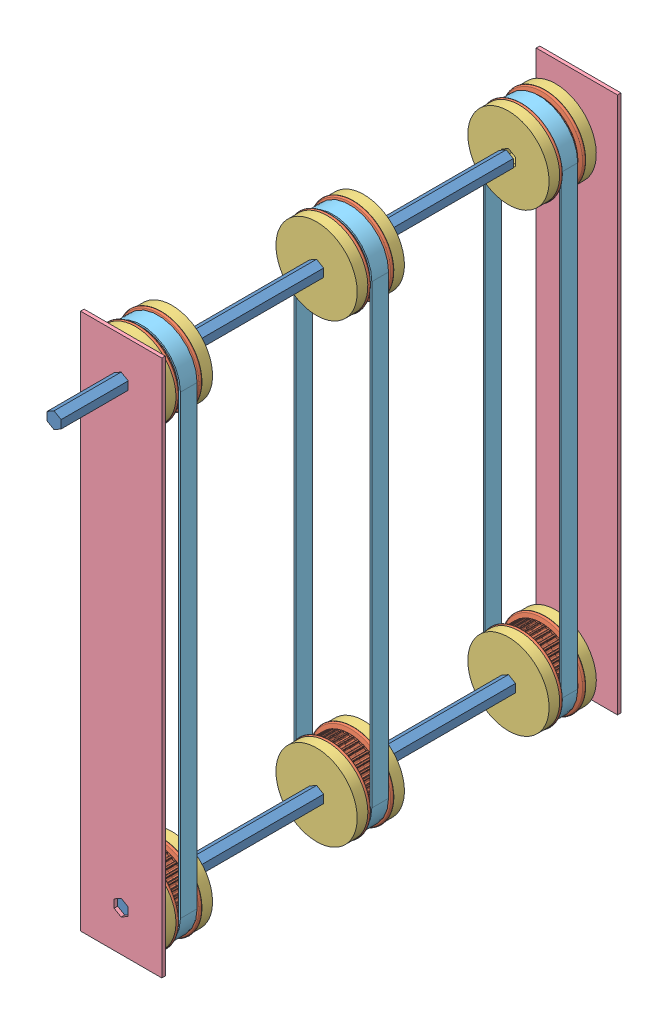
SolidWorks assembly Collection, configuration Default. Lengths in mm.
Overall size (103.22 501.51 473.08).
38 component instances, 5 part files, 17 mates.
Components (placement in the parent):
- HexRod-1: HexRod [Default] at (158.1244 213.3282 311.0594) size (12.7 14.66 406.4)
- wheelpulley-1: wheelpulley [Default] at (101.3185 233.0041 546.741) x (0 0 -1) z (0.052324 -0.99863 0) size (42.43 76.75 76.75)
  - pulley-1: pulley [Default] at (45.3639 55.6985 22.6212) size (13 74.23 74.23)
  - pulley-2: pulley [Default] at (62.0263 55.6985 22.6212) x (-1 0 0) z (0 0.000084 1) size (13 74.23 74.23)
  - wheel-1: wheel [Default] at (70.1462 55.6985 22.6212) x (1 0 0) z (0 -0.99863 -0.052324) size (9.53 73.03 73.03)
  - wheel-2: wheel [Default] at (37.244 55.6985 22.6212) x (1 0 0) z (0 -0.99863 -0.052324) size (9.53 73.03 73.03)
- wheelpulley-2: wheelpulley [Default] at (101.3185 233.0041 374.275) x (0 0 -1) z (0.052324 -0.99863 0) size (42.43 76.75 76.75)
  - pulley-1: pulley [Default] at (45.3639 55.6985 22.6212) size (13 74.23 74.23)
  - pulley-2: pulley [Default] at (62.0263 55.6985 22.6212) x (-1 0 0) z (0 0.000084 1) size (13 74.23 74.23)
  - wheel-1: wheel [Default] at (70.1462 55.6985 22.6212) x (1 0 0) z (0 -0.99863 -0.052324) size (9.53 73.03 73.03)
  - wheel-2: wheel [Default] at (37.244 55.6985 22.6212) x (1 0 0) z (0 -0.99863 -0.052324) size (9.53 73.03 73.03)
- wheelpulley-3: wheelpulley [Default] at (101.3185 233.0041 201.809) x (0 0 -1) z (0.052324 -0.99863 0) size (42.43 76.75 76.75)
  - pulley-1: pulley [Default] at (45.3639 55.6985 22.6212) size (13 74.23 74.23)
  - pulley-2: pulley [Default] at (62.0263 55.6985 22.6212) x (-1 0 0) z (0 0.000084 1) size (13 74.23 74.23)
  - wheel-1: wheel [Default] at (70.1462 55.6985 22.6212) x (1 0 0) z (0 -0.99863 -0.052324) size (9.53 73.03 73.03)
  - wheel-2: wheel [Default] at (37.244 55.6985 22.6212) x (1 0 0) z (0 -0.99863 -0.052324) size (9.53 73.03 73.03)
- wheelplate-1: wheelplate [Default] at (158.1244 213.3282 515.8469) x (0 0 -1) z (1 0 0) size (3.17 482.6 73.03)
- wheelplate-2: wheelplate [Default] at (158.1244 213.3282 106.2719) x (0 0 -1) z (1 0 0) size (3.17 482.6 73.03)
- CollectSub-1: CollectSub [Default] at (376.0703 456.2047 78.0182) size (103.22 103.22 450.86)
  - HexRod-1: HexRod [Default] at (-217.9459 166.6985 296.5412) size (12.7 14.66 406.4)
  - wheelpulley-1: wheelpulley [Default] at (-263.3886 127.3412 468.7227) x (0 0 -1) z (0.891001 -0.454001 0) size (42.43 76.75 76.75)
    - pulley-1: pulley [Default] at (45.3639 55.6985 22.6212) size (13 74.23 74.23)
    - pulley-2: pulley [Default] at (62.0263 55.6985 22.6212) x (-1 0 0) z (0 0.000084 1) size (13 74.23 74.23)
    - wheel-1: wheel [Default] at (70.1462 55.6985 22.6212) x (1 0 0) z (0 -0.99863 -0.052324) size (9.53 73.03 73.03)
    - wheel-2: wheel [Default] at (37.244 55.6985 22.6212) x (1 0 0) z (0 -0.99863 -0.052324) size (9.53 73.03 73.03)
  - wheelpulley-2: wheelpulley [Default] at (-263.3886 127.3412 296.2567) x (0 0 -1) z (0.891001 -0.454001 0) size (42.43 76.75 76.75)
    - pulley-1: pulley [Default] at (45.3639 55.6985 22.6212) size (13 74.23 74.23)
    - pulley-2: pulley [Default] at (62.0263 55.6985 22.6212) x (-1 0 0) z (0 0.000084 1) size (13 74.23 74.23)
    - wheel-1: wheel [Default] at (70.1462 55.6985 22.6212) x (1 0 0) z (0 -0.99863 -0.052324) size (9.53 73.03 73.03)
    - wheel-2: wheel [Default] at (37.244 55.6985 22.6212) x (1 0 0) z (0 -0.99863 -0.052324) size (9.53 73.03 73.03)
  - wheelpulley-3: wheelpulley [Default] at (-263.3886 127.3412 123.7907) x (0 0 -1) z (0.891001 -0.454001 0) size (42.43 76.75 76.75)
    - pulley-1: pulley [Default] at (45.3639 55.6985 22.6212) size (13 74.23 74.23)
    - pulley-2: pulley [Default] at (62.0263 55.6985 22.6212) x (-1 0 0) z (0 0.000084 1) size (13 74.23 74.23)
    - wheel-1: wheel [Default] at (70.1462 55.6985 22.6212) x (1 0 0) z (0 -0.99863 -0.052324) size (9.53 73.03 73.03)
    - wheel-2: wheel [Default] at (37.244 55.6985 22.6212) x (1 0 0) z (0 -0.99863 -0.052324) size (9.53 73.03 73.03)
- Belt-gates 10mm wide-2: Belt-gates 10mm wide [Default] at (158.1371 418.0522 319.5804) x (0 0 1) z (0.000062 -1 0) size (15 69.9 479.58)
- Belt-gates 10mm wide-3: Belt-gates 10mm wide [Default] at (158.1371 418.0522 491.638) x (0 0 1) z (0.000062 -1 0) size (15 69.9 479.58)
- Belt-gates 10mm wide-4: Belt-gates 10mm wide [Default] at (158.1371 418.0522 149.5217) x (0 0 1) z (0.000062 -1 0) size (15 69.9 479.58)
Mates (geometry in assembly coordinates):
- Coincident6: coincident anti-aligned: plane of HexRod-1 through (151.7744 216.9944 514.2594) normal (-1 0 0); plane of wheelpulley-1/wheel-2 through (151.7744 209.6621 504.7344) normal (1 0 0)
- Coincident7: coincident anti-aligned: plane of HexRod-1 through (158.1244 205.9959 514.2594) normal (0.5 -0.866025 0); plane of wheelpulley-1/wheel-2 through (164.4744 209.6621 504.7344) normal (-0.5 0.866025 0)
- Coincident8: coincident aligned: plane of HexRod-1 through (158.1244 213.3282 514.2594) normal (0 0 1); plane of wheelpulley-1/wheel-2 through (158.1244 213.3282 514.2594) normal (0 0 1)
- Coincident9: coincident anti-aligned: line of HexRod-1 through (151.7744 216.9944 514.2594) axis (0 -1 0); line of wheelplate-1 through (151.7744 209.6621 514.2594) axis (0 1 0)
- Parallel1: parallel aligned: plane of wheelpulley-1/wheel-2 through (158.1244 213.3282 514.2594) normal (0 0 1); plane of wheelplate-1 through (158.1244 213.3282 517.4344) normal (0 0 1)
- Coincident11: coincident anti-aligned: line of HexRod-1 through (151.7744 209.6621 514.2594) axis (0.866025 -0.5 0); line of wheelplate-1 through (158.1244 205.9959 514.2594) axis (-0.866025 0.5 0)
- Coincident12: coincident anti-aligned: plane of wheelplate-1 through (158.1244 213.3282 514.2594) normal (0 0 -1); plane of CollectSub-1/wheelpulley-1/wheel-2 through (158.1244 622.9032 514.2594) normal (0 0 1)
- Coincident15: coincident aligned: line of wheelplate-1 through (151.7744 619.2371 514.2594) axis (0 1 0); line of CollectSub-1/wheelpulley-1/wheel-2 through (151.7744 619.2371 514.2594) axis (0 1 0)
- Coincident16: coincident aligned: line of wheelplate-1 through (151.7744 626.5694 514.2594) axis (0.866025 0.5 0); line of CollectSub-1/wheelpulley-1/wheel-2 through (151.7744 626.5694 514.2594) axis (0.866025 0.5 0)
- Concentric3: concentric aligned: cylinder of CollectSub-1/wheelpulley-2/wheel-1 through (158.1244 622.9032 299.3663) axis (0 0 1) radius 36.5125; circle of Belt-gates 10mm wide-2
- Coincident17: coincident: cone of CollectSub-1/wheelpulley-2/pulley-2 through (158.1244 622.9032 311.3447) axis (0 0 1); circle of Belt-gates 10mm wide-2
- Concentric4: concentric aligned: cylinder of Belt-gates 10mm wide-2 through (158.1244 622.9032 327.0804) axis (0 0 -1) radius 34.9504; cylinder of Belt-gates 10mm wide-4 through (158.1244 622.9032 157.0217) axis (0 0 -1) radius 34.9504
- Coincident18: coincident: cone of CollectSub-1/wheelpulley-3/pulley-1 through (158.1244 622.9032 157.349) axis (0 0 -1); circle of Belt-gates 10mm wide-4
- Concentric5: concentric anti-aligned: cylinder of CollectSub-1/wheelpulley-1/wheel-1 through (158.1244 622.9032 471.8323) axis (0 0 1) radius 36.5125; cylinder of Belt-gates 10mm wide-3 through (158.1244 622.9032 499.138) axis (0 0 -1) radius 34.9504
- Coincident19: coincident: cone of CollectSub-1/wheelpulley-1/pulley-2 through (158.1244 622.9032 483.8107) axis (0 0 1); circle of Belt-gates 10mm wide-3
- Symmetric1: symmetric anti-aligned: plane of Belt-gates 10mm wide-2 through (193.0748 213.2012 327.0804) normal (1 0 0); plane of Belt-gates 10mm wide-3 through (193.0748 213.2012 499.138) normal (1 0 0); plane of Belt-gates 10mm wide-4 through (193.0748 213.2012 157.0217) normal (1 0 0)
- Parallel4: parallel aligned: plane of Belt-gates 10mm wide-2 through (193.0748 213.2012 327.0804) normal (1 0 0); plane of assembly through (0 0 0) normal (1 0 0)
